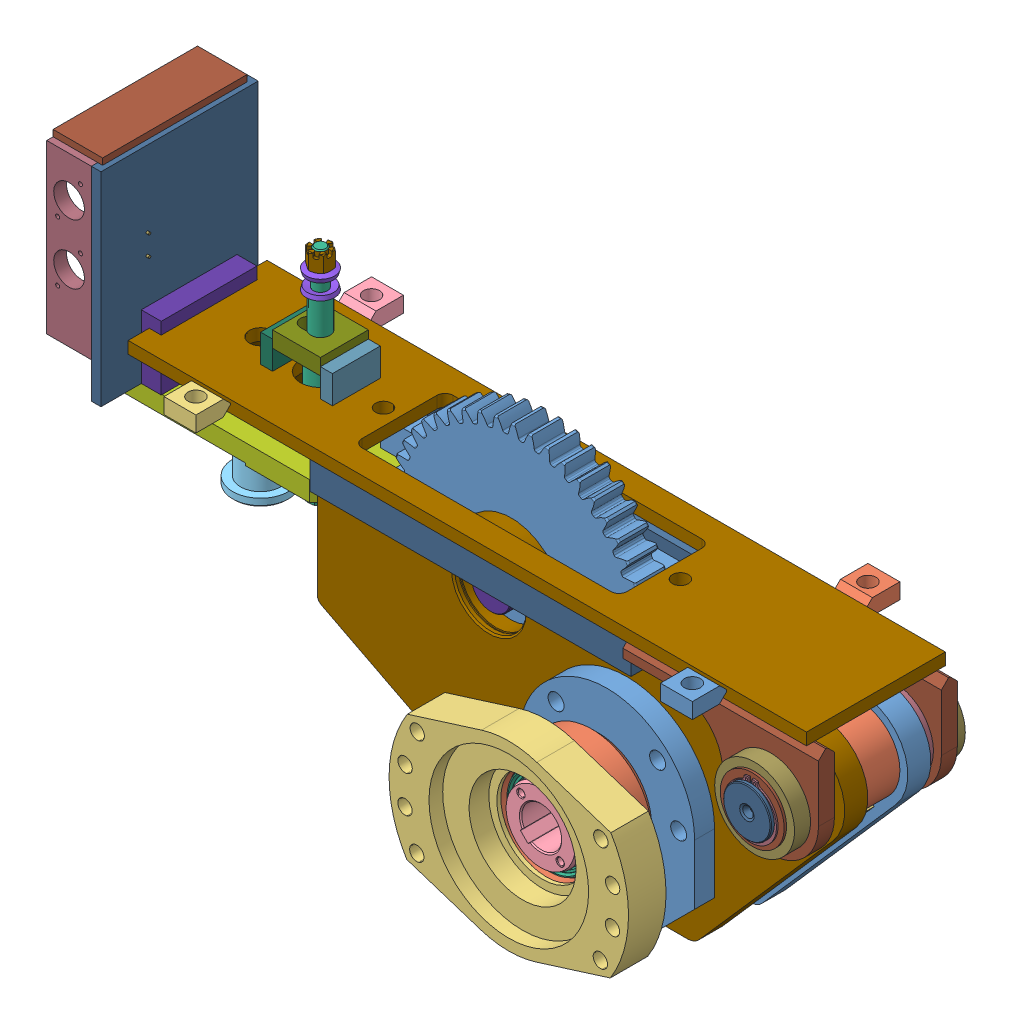
SolidWorks assembly g1_3_1_1, configuration 默认. Lengths in mm.
Overall size (943 530 331.8).
108 component instances, 73 part files, 33 mates.
Components (placement in the parent):
- g1_3_1_1_5_1-1: g1_3_1_1_5_1 [默认] at (1556.1961 -95 30) x (-1 0 0) z (0 1 0) size (926 108 318.6)
  - g1_3_1_1_5-1_af1_1-1: g1_3_1_1_5-1_af1_1 [默认] at origin size (661 29 318.6)
  - g1_3_1_1_5-2_af0_1-1: g1_3_1_1_5-2_af0_1 [默认] at (-213.2 29 0) size (100 50 100)
  - g1_3_1_1_5-4_1-1: g1_3_1_1_5-4_1 [默认] at (-149.9151 54 -132.7301) x (0 1 0) z (-0.659692 0 0.751536) size (50 10 223)
  - g1_3_1_1_5-5_1-1: g1_3_1_1_5-5_1 [默认] at (20.5 54 -217) x (1 0 0) z (0 1 0) size (194 10 50)
  - g1_3_1_1_5-6_1-1: g1_3_1_1_5-6_1 [默认] at (248.4498 54 -161.5242) x (0 1 0) z (0.890083 0 0.455798) size (50 10 284)
  - g1_3_1_1_5-7_1-1: g1_3_1_1_5-7_1 [默认] at (377.8 54 -43.9) x (0 0 -1) z (0 1 0) size (87 10 50)
  - g1_3_1_1_5-9_af0_1-1: g1_3_1_1_5-9_af0_1 [默认] at (502.8 54 24.6) x (1 0 0) z (0 1 0) size (300 25 108)
  - g1_3_1_1_5-8_1-1: g1_3_1_1_5-8_1 [默认] at (437.8 54 49.6) x (1 0 0) z (0 1 0) size (60 50 60)
  - g1_3_1_1_5-1_af0_1-1: g1_3_1_1_5-1_af0_1 [默认] at (0 79 0) size (661 29 318.6)
- g1_3_1_1_4_1-1: g1_3_1_1_4_1 [默认] at (1769.3961 -95 -33.3) x (1 0 0) z (0 -1 0) size (80 234 80)
  - g1_3_1_1_4-1_1-1: g1_3_1_1_4-1_1 [默认] at origin size (60 234 60.04)
  - g1_3_1_1_4-3_1-2: g1_3_1_1_4-3_1 [默认] at (0 224.3 0) size (80 3 80)
  - g1_3_1_1_4-2_1-1: g1_3_1_1_4-2_1 [默认] at (0 174.3 0) size (72 50 72)
  - g1_3_1_1_4-2_1-2: g1_3_1_1_4-2_1 [默认] at (0 9.7 0) size (72 50 72)
  - g1_3_1_1_4-2_1-3: g1_3_1_1_4-2_1 [默认] at (0 62.7 0) size (72 50 72)
  - g1_3_1_1_4-2_1-4: g1_3_1_1_4-2_1 [默认] at (0 121.3 0) size (72 50 72)
  - 60_gb894_1_1-2: 60_gb894_1_1 [默认] at (1.95 227.5 -28.4332) x (-1 0 0) z (0 1 0) size (65.16 69.76 2)
- g1_3_1_1_2_1-1: g1_3_1_1_2_1 [默认] at (1556.1961 -195.4 0) x (0.99999 -0.004549 0) z (-0.004549 -0.99999 0) size (219.6 152 245)
  - g1_3_1_1_2-1_1-1: g1_3_1_1_2-1_1 [默认] at origin size (219.6 61 245)
  - g1_3_1_1_2-2_1-1: g1_3_1_1_2-2_1 [默认] at (0 152 0) x (-0.047609 0 0.998866) z (0 1 0) size (120.16 120.16 117)
  - g1_3_1_1_2-3_1-1: g1_3_1_1_2-3_1 [默认] at (-20.1525 129 20.1525) x (0 -1 0) z (0.707107 0 0.707107) size (28 11 14)
- g1_3_1_1_3_1-1: g1_3_1_1_3_1 [默认] at (1383.3961 -78.4 83.75) x (0 0 -1) z (0 -1 0) size (103.5 321.87 322.01)
  - g1_3_1_1_3-1_1-1: g1_3_1_1_3-1_1 [默认] at origin size (103.5 52 52)
  - 16x10x45_gb1096_1-1: 16x10x45_gb1096_1 [默认] at (-0.5 0 25) x (1 0 0) z (0 0 -1) size (45 16 10)
  - _X2_60F08F6E_X0_g1_3_1_1_3-2_1-1: _X2_60F08F6E_X0_g1_3_1_1_3-2_1 [默认] at (25 0 0) x (0 0 1) z (1 0 0) size (322.01 321.87 50.08)
- g1_3_1_1_1_2-1: g1_3_1_1_1_2 [默认] at (1556.1961 -195.4 123.8) x (0.99999 -0.004549 0) z (-0.004549 -0.99999 0) size (300 165.8 228)
  - g1_3_1_1_1_1_1-1: g1_3_1_1_1_1_1 [默认] at origin size (300 112 228)
    - g1_3_1_1_1_1-2_af0_1-1: g1_3_1_1_1_1-2_af0_1 [默认] at (0 50 0) size (150 65 150)
    - g1_3_1_1_1_1-3_af0_1-1: g1_3_1_1_1_1-3_af0_1 [默认] at (0 140 0) size (300 47 228)
  - g1_3_1_1_1-2_1-1: g1_3_1_1_1-2_1 [默认] at (0 122.2 0) x (0.707107 0 0.707107) z (0.707107 0 -0.707107) size (90 126 90)
  - g1_3_1_1_1-1_1-1: g1_3_1_1_1-1_1 [默认] at (0 77 0) x (0 1 0) z (0 0 1) size (20 110 110)
  - b90x110x12_gb9877_1_1-1: b90x110x12_gb9877_1_1 [默认] at (0 66.9 0) size (108.6 17.9 108.6)
    - b90x110x12_gb9877_1_rubber_1-1: b90x110x12_gb9877_1_rubber_1 [默认] at origin size (108.6 12 108.6)
    - b90x110x12_gb9877_1_frame_1-1: b90x110x12_gb9877_1_frame_1 [默认] at (0 -2.4 0) x (-1 0 0) z (0 0 1) size (107.2 9.5 107.2)
  - b90x110x12_gb9877_1_1-2: b90x110x12_gb9877_1_1 [默认] at (0 104.8 0) size (108.6 17.9 108.6)
    - b90x110x12_gb9877_1_rubber_1-1: b90x110x12_gb9877_1_rubber_1 [默认] at origin size (108.6 12 108.6)
    - b90x110x12_gb9877_1_frame_1-1: b90x110x12_gb9877_1_frame_1 [默认] at (0 -2.4 0) x (-1 0 0) z (0 0 1) size (107.2 9.5 107.2)
  - 80_gb894_1_1-1: 80_gb894_1_1 [默认] at (-2.4 11.1 -38.1746) x (1 0 0) z (0 -1 0) size (85.83 90.87 2.5)
- g1_3_1_1_6_1-1: g1_3_1_1_6_1 [默认] at (1383.3961 0 84) x (-1 0 0) z (0 0 1) size (875 200 260)
  - g1_3_1_1_6-4_af0_1-1: g1_3_1_1_6-4_af0_1 [默认] at origin size (850 15 174)
  - g1_3_1_1_6-8_1-1: g1_3_1_1_6-8_1 [默认] at (0 40 57) x (1 0 0) z (0 -1 0) size (402 20 44.8)
  - g1_3_1_1_6-8_1-2: g1_3_1_1_6-8_1 [默认] at (0 40 -77) x (1 0 0) z (0 -1 0) size (402 20 44.8)
  - g1_3_1_1_6-1_1-1: g1_3_1_1_6-1_1 [默认] at (-386 95 -87) x (1 0 0) z (0 -1 0) size (245 20 140)
  - g1_3_1_1_6-1_1-2: g1_3_1_1_6-1_1 [默认] at (-386 95 67) x (1 0 0) z (0 -1 0) size (245 20 140)
  - g1_3_1_1_6-3_1-1: g1_3_1_1_6-3_1 [默认] at (-386 95 87) x (-1 0 0) z (0 1 0) size (100 20 100)
  - g1_3_1_1_6-3_1-2: g1_3_1_1_6-3_1 [默认] at (-386 95 -107) x (-1 0 0) z (0 1 0) size (100 20 100)
  - g1_3_1_1_6-2_1-1: g1_3_1_1_6-2_1 [默认] at (-386 95 57) x (-1 0 0) z (0 1 0) size (100 10 100)
  - g1_3_1_1_6-2_1-2: g1_3_1_1_6-2_1 [默认] at (-386 95 -57) x (1 0 0) z (0 1 0) size (100 10 100)
  - g1_3_1_1_6-9_1-1: g1_3_1_1_6-9_1 [默认] at (220 -17 0) x (0 1 0) z (0 0 -1) size (35 15 60)
  - g1_3_1_1_6-9_af0_1-1: g1_3_1_1_6-9_af0_1 [默认] at (310 -17 0) x (0 1 0) z (0 0 1) size (35 15 60)
  - g1_3_1_1_6-10_1-1: g1_3_1_1_6-10_1 [默认] at (265 -45 0) size (60 20 60)
  - g1_3_1_1_6-12_af0_1-1: g1_3_1_1_6-12_af0_1 [默认] at (434 25 0.5) x (0 0 1) z (0 -1 0) size (120 25 80)
  - g1_3_1_1_6-11_af0_1-1: g1_3_1_1_6-11_af0_1 [默认] at (357 15 0) size (94 40 60)
  - g1_3_1_1_6-5_af0_1-1: g1_3_1_1_6-5_af0_1 [默认] at (-311 -5 108.5) x (0 0 -1) z (1 0 0) size (43 19.6 40)
  - g1_3_1_1_6-5_af1_1-1: g1_3_1_1_6-5_af1_1 [默认] at (-311 -5 -108.5) x (0 0 1) z (-1 0 0) size (43 19.6 40)
  - g1_3_1_1_6-5_af2_1-1: g1_3_1_1_6-5_af2_1 [默认] at (311 -5 108.5) x (0 0 -1) z (1 0 0) size (43 19.6 40)
  - g1_3_1_1_6-5_af3_1-1: g1_3_1_1_6-5_af3_1 [默认] at (311 -5 -108.5) x (0 0 1) z (-1 0 0) size (43 19.6 40)
- g1_3_1_1-1_1-1: g1_3_1_1-1_1 [默认] at (1043.3961 -50.5 84) x (0.837169 0 0.546944) z (0.546944 0 -0.837169) size (70 135 70)
- g1_3_1_1_7_1-1: g1_3_1_1_7_1 [默认] at (1118.3961 49.5833 84) x (0 1 0) z (0.554222 0 -0.832369) size (272.02 63.51 60)
  - g1_3_1_1_7-1_1-1: g1_3_1_1_7-1_1 [默认] at origin size (272.02 60 60)
  - g1_3_1_1_7-2_1-1: g1_3_1_1_7-2_1 [默认] at (-104.3833 -31.7543 0) x (0 1 0) z (1 0 0) size (63.51 55 25)
  - a35_5_gb1972_1-1: a35_5_gb1972_1 [默认] at (39.2167 0 0) x (0 0.075145 0.997173) z (0 0.997173 -0.075145) size (35.5 7.2 35.5)
  - a35_5_gb1972_1-2: a35_5_gb1972_1 [默认] at (62.8167 0 0) x (0 -0.99777 0.066751) z (0 -0.066751 -0.99777) size (35.5 7.2 35.5)
  - m16a_gb6178_1-1: m16a_gb6178_1 [默认] at (85.8167 13.8564 0) x (0 -1 0) z (-1 0 0) size (27.71 24 20.8)
- g1_3_1_1_8_1-1: g1_3_1_1_8_1 [默认] at (954.3961 62.5 96.5) x (0 0 -1) z (0 1 0) size (197 71 268.3)
  - g1_3_1_1_8_1_af0_1-1: g1_3_1_1_8_1_af0_1 [默认] at origin size (197 68 263)
    - g1_3_1_1_8_1-3_af1_1-1: g1_3_1_1_8_1-3_af1_1 [默认] at origin size (197 12 255)
    - g1_3_1_1_8_1-1_1-1: g1_3_1_1_8_1-1_1 [默认] at (0 37 127.5) x (1 0 0) z (0 -1 0) size (181 8 62)
    - g1_3_1_1_8_1-2_af1_1-1: g1_3_1_1_8_1-2_af1_1 [默认] at (98.5 40 22.5) x (0 1 0) z (0 0 1) size (56 16 210)
    - g1_3_1_1_8_1-2_af0_1-1: g1_3_1_1_8_1-2_af0_1 [默认] at (-98.5 40 22.5) x (0 1 0) z (0 0 -1) size (56 16 210)
    - g1_3_1_1_8_1-5_1-1: g1_3_1_1_8_1-5_1 [默认] at (0 40 -82.5) x (1 0 0) z (0 1 0) size (165 8 56)
    - g1_3_1_1_8_1-6_1-1: g1_3_1_1_8_1-6_1 [默认] at (27.5 40 -106) x (0 1 0) z (0 0 -1) size (56 6 31)
    - g1_3_1_1_8_1-6_1-2: g1_3_1_1_8_1-6_1 [默认] at (-8.5 40 -106) x (0 1 0) z (0 0 -1) size (56 6 31)
    - g1_3_1_1_8_1-4_af1_1-1: g1_3_1_1_8_1-4_af1_1 [默认] at (-10 12 5) size (105 17 85)
    - g1_3_1_1_8_1-8_af0_1-1: g1_3_1_1_8_1-8_af0_1 [默认] at (12.5 40 -127.5) x (0 1 0) z (1 0 0) size (56 6 54)
    - g1_3_1_1_8_1_af0_more_1-1: g1_3_1_1_8_1_af0_more_1 [默认] at origin size (197 61 238)
  - g1_3_1_1_8-3_1-1: g1_3_1_1_8-3_1 [默认] at (12.5 37 -32.7987) x (0 0 -1) z (0 1 0) size (229 15 15)
  - g1_3_1_1_8-6_1-1: g1_3_1_1_8-6_1 [默认] at (12.5 37 30.1) x (-1 0 0) z (0 1 0) size (26 60 26)
  - g1_3_1_1_8-5_1-1: g1_3_1_1_8-5_1 [默认] at (12.5 29 -27.5) size (60 24 20)
  - g1_3_1_1_8-9_af0_1-1: g1_3_1_1_8-9_af0_1 [默认] at (-42.5 17 5.5) size (34 10 74)
  - g1_3_1_1_8-10_1-1: g1_3_1_1_8-10_1 [默认] at (12.5 37 -127.5) x (1 0 0) z (0 1 0) size (40 2 32)
  - ya2x20x90-2_gb2089_af0_1-1: ya2x20x90-2_gb2089_af0_1 [默认] at (12.5 37 -82.5) x (0 0 -1) z (1 0 0) size (92.3 24.62 24.71)
  - 14x2_65_gb3452_1_1-1: 14x2_65_gb3452_1_1 [默认] at (12.5 37 -124.5) x (0 0 1) z (0 1 0) size (2.65 19.38 19.38)
  - 15_gb894_1_1-1: 15_gb894_1_1 [默认] at (12 29.8675 -73.9) size (17.18 18.67 1.11)
  - 15_gb894_1_1-2: 15_gb894_1_1 [默认] at (12 29.8675 29) size (17.18 18.67 1.11)
  - 8_gb93_1-1: 8_gb93_1 [默认] at (32.5 53 -27.5) x (-1 0 0) z (0 1 0) size (12.3 12.3 2.1)
  - m8x40_gb5782_1-1: m8x40_gb5782_1 [默认] at (32.5 55.1 -27.5) size (15.01 45.3 13)
  - 8_gb93_1-2: 8_gb93_1 [默认] at (-7.5 53 -27.5) x (-1 0 0) z (0 1 0) size (12.3 12.3 2.1)
  - m8x40_gb5782_1-2: m8x40_gb5782_1 [默认] at (-7.5 55.1 -27.5) size (15.01 45.3 13)
  - m3x10_gb818_1-1: m3x10_gb818_1 [默认] at (57.5 2 60.5) size (5.81 12.5 5.77)
  - m3x10_gb818_1-2: m3x10_gb818_1 [默认] at (57.5 2 100.5) size (5.81 12.5 5.77)
  - m3x10_gb818_1-3: m3x10_gb818_1 [默认] at (-17.5 2 100.5) size (5.81 12.5 5.77)
  - m3x10_gb818_1-4: m3x10_gb818_1 [默认] at (-57.5 2 100.5) size (5.81 12.5 5.77)
  - m3x30_gb818_1-1: m3x30_gb818_1 [默认] at (-40.5 -3 7.5) size (5.81 32.5 5.77)
  - m3x30_gb818_1-2: m3x30_gb818_1 [默认] at (-40.5 -3 32.9) size (5.81 32.5 5.77)
  - 6_gb93_1-9: 6_gb93_1 [默认] at (-52.5 28.6 -17.5) x (1 0 0) z (0 -1 0) size (9.3 9.3 1.6)
  - m6x20_gb5783_1-9: m6x20_gb5783_1 [默认] at (-52.5 28.6 -17.5) size (11.55 24 10)
  - 6_gb93_1-10: 6_gb93_1 [默认] at (-32.5 28.6 -17.5) x (1 0 0) z (0 -1 0) size (9.3 9.3 1.6)
  - m6x20_gb5783_1-10: m6x20_gb5783_1 [默认] at (-32.5 28.6 -17.5) size (11.55 24 10)
  - 5x14_gb119_2_1-1: 5x14_gb119_2_1 [默认] at (-42.5 27 -3.5) size (5 14 5)
  - m3x6_gb818_1-1: m3x6_gb818_1 [默认] at (27.5 37 -123.5) x (1 0 0) z (0 1 0) size (5.81 8.5 5.77)
  - m3x6_gb818_1-2: m3x6_gb818_1 [默认] at (-2.5 37 -123.5) x (1 0 0) z (0 1 0) size (5.81 8.5 5.77)
- _X2_57AB5708_X0_16_gb93_1-9: _X2_57AB5708_X0_16_gb93_1 [默认] at (942.3961 -50 44) x (0 0.924225 0.381849) z (-1 0 0) size (24.4 24.4 4.1)
- _X2_87BA6813_X0_m16x35_gb5783_10_1-1: _X2_87BA6813_X0_m16x35_gb5783_10_1 [默认] at (938.2961 -50 44) x (0 -0.924225 -0.381849) z (0 0.381849 -0.924225) size (27.71 45 24)
- _X2_57AB5708_X0_16_gb93_1-10: _X2_57AB5708_X0_16_gb93_1 [默认] at (942.3961 -50 124) x (0 0.924225 0.381849) z (-1 0 0) size (24.4 24.4 4.1)
- _X2_87BA6813_X0_m16x35_gb5783_10_1-2: _X2_87BA6813_X0_m16x35_gb5783_10_1 [默认] at (938.2961 -50 124) x (0 -0.924225 -0.381849) z (0 0.381849 -0.924225) size (27.71 45 24)
- g1_3_1_1_1_1-1_af0_1-1: g1_3_1_1_1_1-1_af0_1 [默认] at (1556.1961 -195.4 113) x (1 0 0) z (0 -1 0) size (220 42 245)
Mates (geometry in assembly coordinates):
- 重合1: coincident anti-aligned: plane of g1_3_1_1_2_1-1/g1_3_1_1_2-3_1-1 through (1531.0249 -210.4885 129) normal (-0.703883 0.710316 0); plane of g1_3_1_1_1_2-1/g1_3_1_1_1-2_1-1 through (1530.8118 -210.6996 246) normal (0.703883 -0.710316 0)
- 重合2: coincident anti-aligned: plane of g1_3_1_1_2_1-1/g1_3_1_1_2-2_1-1 through (1556.1961 -195.4 120) normal (0 0 1); plane of g1_3_1_1_1_2-1/g1_3_1_1_1-2_1-1 through (1556.1961 -195.4 120) normal (0 0 -1)
- 同心3: concentric aligned: cylinder of g1_3_1_1_2_1-1/g1_3_1_1_2-2_1-1 through (1556.1961 -195.4 29.15) axis (0 0 1) radius 25; cylinder of g1_3_1_1_1_2-1/g1_3_1_1_1-2_1-1 through (1556.1961 -195.4 246) axis (0 0 1) radius 25
- 同心9: concentric anti-aligned: cylinder of g1_3_1_1_8_1-1/g1_3_1_1_8_1_af0_1-1/g1_3_1_1_8_1-3_af1_1-1 through (942.3961 -50 124) axis (1 0 0) radius 8.5; cylinder of _X2_87BA6813_X0_m16x35_gb5783_10_1-2 through (975.0461 -50 124) axis (-1 0 0) radius 8
- 同心12: concentric anti-aligned: cylinder of g1_3_1_1_6_1-1/g1_3_1_1_6-12_af0_1-1 through (997.9124 -50 44) axis (1 0 0) radius 7; cylinder of _X2_87BA6813_X0_m16x35_gb5783_10_1-1 through (975.0461 -50 44) axis (-1 0 0) radius 8
- 同心13: concentric aligned: cylinder of _X2_57AB5708_X0_16_gb93_1-10 through (942.3961 -50 124) axis (-1 0 0) radius 8.1; cylinder of _X2_87BA6813_X0_m16x35_gb5783_10_1-2 through (975.0461 -50 124) axis (-1 0 0) radius 8
- 同心14: concentric aligned: cylinder of _X2_57AB5708_X0_16_gb93_1-9 through (942.3961 -50 44) axis (-1 0 0) radius 8.1; cylinder of _X2_87BA6813_X0_m16x35_gb5783_10_1-1 through (975.0461 -50 44) axis (-1 0 0) radius 8
- 重合3: coincident anti-aligned: plane of _X2_57AB5708_X0_16_gb93_1-9 through (938.2961 -50 44) normal (-1 0 0); plane of _X2_87BA6813_X0_m16x35_gb5783_10_1-1 through (938.2961 -50 44) normal (1 0 0)
- 重合4: coincident anti-aligned: plane of _X2_57AB5708_X0_16_gb93_1-10 through (938.2961 -50 124) normal (-1 0 0); plane of _X2_87BA6813_X0_m16x35_gb5783_10_1-2 through (938.2961 -50 124) normal (1 0 0)
- 同心15: concentric aligned: cylinder of g1_3_1_1_8_1-1/g1_3_1_1_8_1_af0_1-1/g1_3_1_1_8_1-3_af1_1-1 through (942.3961 -50 44) axis (-1 0 0) radius 8.5; cylinder of _X2_87BA6813_X0_m16x35_gb5783_10_1-1 through (975.0461 -50 44) axis (-1 0 0) radius 8
- 同心18: concentric aligned: cylinder of g1_3_1_1_6_1-1/g1_3_1_1_6-11_af0_1-1 through (1043.3961 71.0063 84) axis (0 -1 0) radius 14; cylinder of g1_3_1_1-1_1-1 through (1043.3961 -24.25 84) axis (0 -1 0) radius 15
- 重合9: coincident aligned: plane of g1_3_1_1_6_1-1/g1_3_1_1_6-11_af0_1-1 through (1073.3961 -50.5 114) normal (0 -1 0); plane of g1_3_1_1-1_1-1 through (1043.3961 -50.5 84) normal (0 -1 0)
- 同心20: concentric anti-aligned: cylinder of g1_3_1_1_5_1-1/g1_3_1_1_5-9_af0_1-1 through (1043.3961 -95.4 84) axis (0 1 0) radius 27; cylinder of g1_3_1_1-1_1-1 through (1043.3961 -55.5 84) axis (0 -1 0) radius 25
- 重合10: coincident anti-aligned: plane of g1_3_1_1_8_1-1/g1_3_1_1_8_1_af0_1-1/g1_3_1_1_8_1-3_af1_1-1 through (942.3961 62.5 96.5) normal (-1 0 0); plane of _X2_57AB5708_X0_16_gb93_1-9 through (942.3961 -50 44) normal (1 0 0)
- 重合12: coincident anti-aligned: plane of g1_3_1_1_8_1-1/g1_3_1_1_8_1_af0_1-1/g1_3_1_1_8_1-3_af1_1-1 through (942.3961 62.5 96.5) normal (-1 0 0); plane of _X2_57AB5708_X0_16_gb93_1-10 through (942.3961 -50 124) normal (1 0 0)
- 同心21: concentric aligned: cylinder of g1_3_1_1_5_1-1/g1_3_1_1_5-8_1-1 through (1118.3961 -103.15 84) axis (0 1 0) radius 14.75; cylinder of g1_3_1_1_7_1-1/g1_3_1_1_7-1_1-1 through (1118.3961 -405.7188 84) axis (0 1 0) radius 16
- 重合13: coincident anti-aligned: plane of g1_3_1_1_6_1-1/g1_3_1_1_6-12_af0_1-1 through (954.3961 0 84) normal (-1 0 0); plane of g1_3_1_1_8_1-1/g1_3_1_1_8_1_af0_1-1/g1_3_1_1_8_1-3_af1_1-1 through (954.3961 62.5 96.5) normal (1 0 0)
- 同心23: concentric aligned: cylinder of g1_3_1_1_5_1-1/g1_3_1_1_5-1_af1_1-1 through (1769.3961 -95 30) axis (0 0 1) radius 36; cylinder of g1_3_1_1_6_1-1/g1_3_1_1_6-3_1-2 through (1769.3961 -95 -23) axis (0 0 1) radius 36
- 同心24: concentric aligned: cylinder of g1_3_1_1_4_1-1/g1_3_1_1_4-2_1-2 through (1769.3961 -95 -23.6) axis (0 0 1) radius 36; cylinder of g1_3_1_1_6_1-1/g1_3_1_1_6-3_1-2 through (1769.3961 -95 -23) axis (0 0 1) radius 36
- 重合14: coincident anti-aligned: plane of g1_3_1_1_4_1-1/g1_3_1_1_4-3_1-2 through (1769.3961 -95 191) normal (0 0 -1); plane of g1_3_1_1_6_1-1/g1_3_1_1_6-3_1-1 through (1769.3961 -95 191) normal (0 0 1)
- 重合15: coincident anti-aligned: plane of g1_3_1_1_5_1-1/g1_3_1_1_5-8_1-1 through (1118.3961 -95.4 84) normal (0 -1 0); plane of g1_3_1_1_7_1-1/g1_3_1_1_7-1_1-1 through (1118.3961 -95.4 84) normal (0 1 0)
- 同心25: concentric aligned: cylinder of g1_3_1_1_5_1-1/g1_3_1_1_5-1_af1_1-1 through (1383.3961 -78.4 30) axis (0 0 1) radius 45; cylinder of g1_3_1_1_3_1-1/g1_3_1_1_3-1_1-1 through (1383.3961 -78.4 26.825) axis (0 0 1) radius 25
- 同心26: concentric aligned: cylinder of g1_3_1_1_5_1-1/g1_3_1_1_5-1_af1_1-1 through (1556.1961 -195.4 30) axis (0 0 1) radius 75; cylinder of g1_3_1_1_2_1-1/g1_3_1_1_2-1_1-1 through (1556.1961 -195.4 30) axis (0 0 1) radius 75
- 重合16: coincident anti-aligned: plane of g1_3_1_1_5_1-1/g1_3_1_1_5-1_af1_1-1 through (1556.1961 -95 30) normal (0 0 -1); plane of g1_3_1_1_2_1-1/g1_3_1_1_2-1_1-1 through (1556.1961 -195.4 30) normal (0 0 1)
- 重合17: coincident anti-aligned: plane of g1_3_1_1_5_1-1/g1_3_1_1_5-1_af1_1-1; plane of ? through (523.5275 -270.9624 278.2595) normal (0 -1 0)
- 重合19: coincident aligned: plane of g1_3_1_1_5_1-1/g1_3_1_1_5-1_af0_1-1 through (1383.3961 -78.4 128.8) normal (0 0 1); plane of g1_3_1_1_3_1-1/g1_3_1_1_3-1_1-1 through (1383.3961 -78.4 128.8) normal (0 0 1)
- 重合28: coincident anti-aligned: plane of g1_3_1_1_2_1-1/g1_3_1_1_2-1_1-1 through (1556.1961 -195.4 0) normal (0 0 -1); plane of assembly through (0 0 0) normal (0 0 1)
- 重合31: coincident aligned: plane of g1_3_1_1_6_1-1/g1_3_1_1_6-4_af0_1-1 through (1383.3961 0 84) normal (0 1 0); plane of assembly through (0 0 0) normal (0 1 0)
- 同心28: concentric aligned: cylinder of g1_3_1_1_6_1-1/g1_3_1_1_6-12_af0_1-1 through (997.9124 -50 124) axis (-1 0 0) radius 7; cylinder of _X2_87BA6813_X0_m16x35_gb5783_10_1-2 through (975.0461 -50 124) axis (-1 0 0) radius 8
- 同心29: concentric aligned: cylinder of g1_3_1_1_5_1-1/g1_3_1_1_5-1_af0_1-1 through (1556.1961 -195.4 109) axis (0 0 1) radius 75; cylinder of g1_3_1_1_1_1-1_af0_1-1 through (1556.1961 -195.4 -384.4109) axis (0 0 1) radius 75
- 同心30: concentric aligned: cylinder of g1_3_1_1_5_1-1/g1_3_1_1_5-1_af0_1-1 through (1492.5961 -131.8 108.5324) axis (0 0 1) radius 5.1; cylinder of g1_3_1_1_1_1-1_af0_1-1 through (1492.5961 -131.8 163) axis (0 0 1) radius 10
- 重合33: coincident anti-aligned: plane of g1_3_1_1_5_1-1/g1_3_1_1_5-1_af0_1-1 through (1556.1961 -95 138) normal (0 0 1); plane of g1_3_1_1_1_1-1_af0_1-1 through (1556.1961 -195.4 138) normal (0 0 -1)
- 平行2: parallel aligned: plane of g1_3_1_1_4_1-1/60_gb894_1_1-2 through (1767.4461 -66.5668 194.2) normal (1 0 0); plane of g1_3_1_1_6_1-1/g1_3_1_1_6-1_1-2 through (1829.3961 -95 151) normal (1 0 0)
